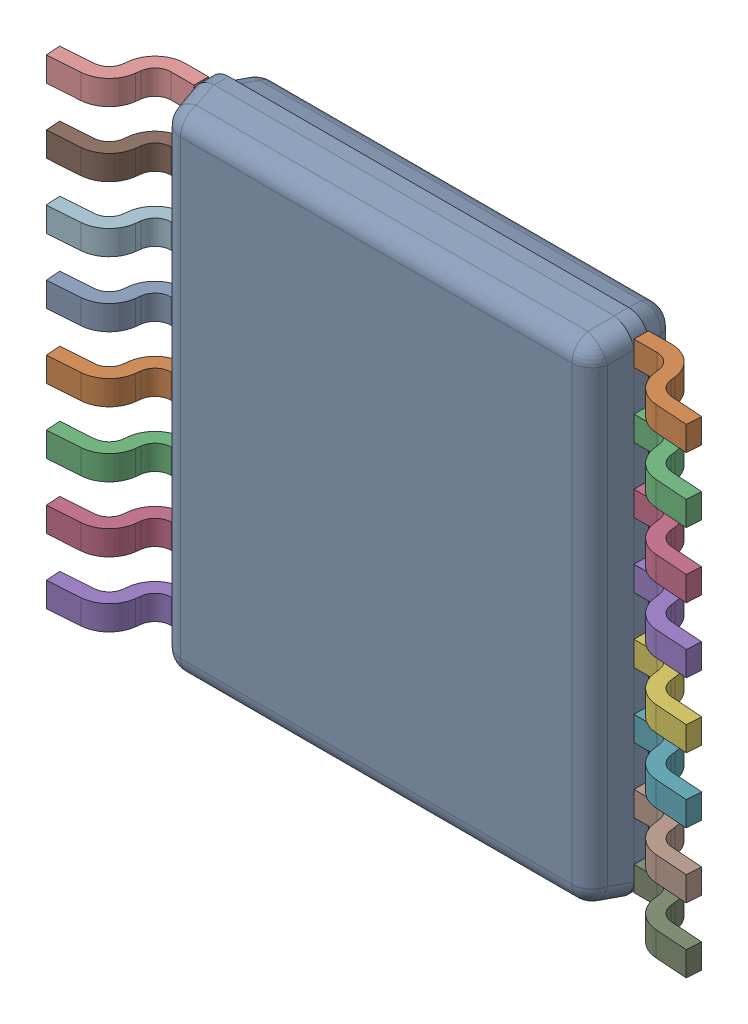
SolidWorks assembly U201PCB, configuration Default. Lengths in mm.
Overall size (6.42 5 1).
18 component instances, 2 part files, 0 mates.
Components (placement in the parent):
- PW0016AakaMTC16-1: PW0016AakaMTC16 [Default] at (126.3999 122.3001 -2.2868) x (0 1 0) z (-1 0 0) size (5 1 6.42)
  - BODY_MTC16-1: BODY_MTC16 [Default] at origin size (5 0.9 4.4)
  - LEAD_MTC16-1: LEAD_MTC16 [Default] at (2.275 -0.3725 -2.6) x (-1 0 0) z (0 0 -1) size (0.25 0.62 1.01)
  - LEAD_MTC16-2: LEAD_MTC16 [Default] at (1.625 -0.3725 -2.6) x (-1 0 0) z (0 0 -1) size (0.25 0.62 1.01)
  - LEAD_MTC16-3: LEAD_MTC16 [Default] at (0.975 -0.3725 -2.6) x (-1 0 0) z (0 0 -1) size (0.25 0.62 1.01)
  - LEAD_MTC16-4: LEAD_MTC16 [Default] at (0.325 -0.3725 -2.6) x (-1 0 0) z (0 0 -1) size (0.25 0.62 1.01)
  - LEAD_MTC16-5: LEAD_MTC16 [Default] at (-0.325 -0.3725 -2.6) x (-1 0 0) z (0 0 -1) size (0.25 0.62 1.01)
  - LEAD_MTC16-6: LEAD_MTC16 [Default] at (-0.975 -0.3725 -2.6) x (-1 0 0) z (0 0 -1) size (0.25 0.62 1.01)
  - LEAD_MTC16-7: LEAD_MTC16 [Default] at (-1.625 -0.3725 -2.6) x (-1 0 0) z (0 0 -1) size (0.25 0.62 1.01)
  - LEAD_MTC16-8: LEAD_MTC16 [Default] at (-2.275 -0.3725 -2.6) x (-1 0 0) z (0 0 -1) size (0.25 0.62 1.01)
  - LEAD_MTC16-9: LEAD_MTC16 [Default] at (2.275 -0.3725 2.6) size (0.25 0.62 1.01)
  - LEAD_MTC16-10: LEAD_MTC16 [Default] at (1.625 -0.3725 2.6) size (0.25 0.62 1.01)
  - LEAD_MTC16-11: LEAD_MTC16 [Default] at (0.975 -0.3725 2.6) size (0.25 0.62 1.01)
  - LEAD_MTC16-12: LEAD_MTC16 [Default] at (0.325 -0.3725 2.6) size (0.25 0.62 1.01)
  - LEAD_MTC16-13: LEAD_MTC16 [Default] at (-0.325 -0.3725 2.6) size (0.25 0.62 1.01)
  - LEAD_MTC16-14: LEAD_MTC16 [Default] at (-0.975 -0.3725 2.6) size (0.25 0.62 1.01)
  - LEAD_MTC16-15: LEAD_MTC16 [Default] at (-1.625 -0.3725 2.6) size (0.25 0.62 1.01)
  - LEAD_MTC16-16: LEAD_MTC16 [Default] at (-2.275 -0.3725 2.6) size (0.25 0.62 1.01)
